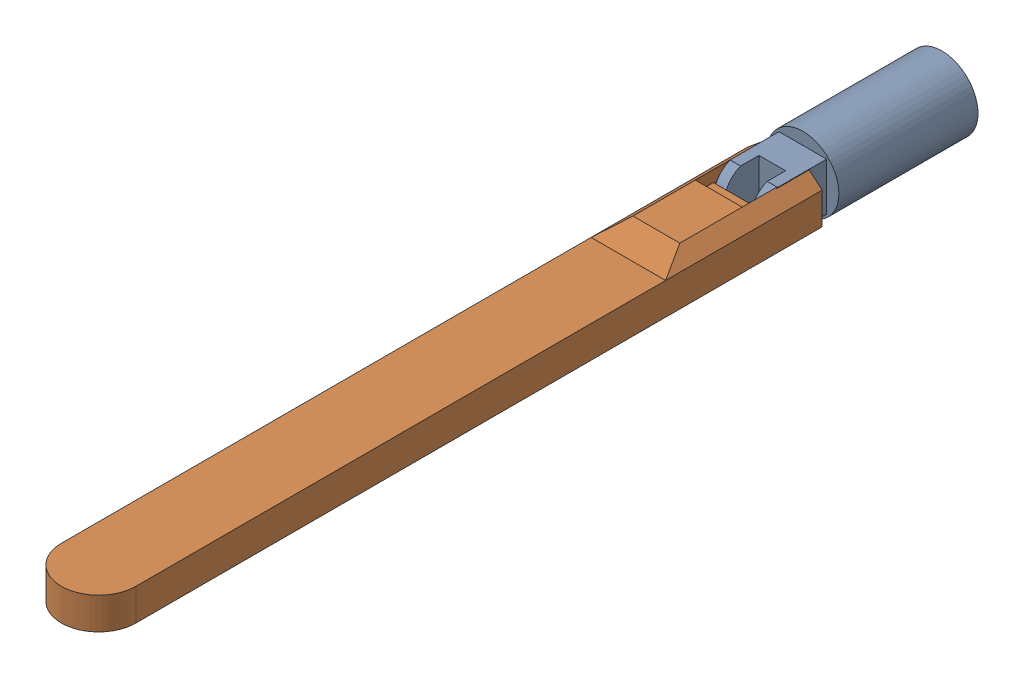
SolidWorks assembly Antannae Assembly, configuration Default. Lengths in mm.
Overall size (13.4 12.95 158.14).
2 component instances, 2 part files, 3 mates.
Components (placement in the parent):
- Antannae for box-1: Antannae for box [Default] at (-76.0672 11.3243 14.0778) size (12.95 12.95 36.74)
- Antannae extender for box-1: Antannae extender for box [Default] at (-76.1605 7.7893 103.8644) x (-1 0 0) z (0 0 -1) size (13.4 9.9 130)
Mates (geometry in assembly coordinates):
- Parallel3: parallel anti-aligned: plane of Antannae for box-1 through (-80.3301 7.0493 47.8778) normal (-1 0 0); plane of Antannae extender for box-1 through (-80.4105 21.1893 50.8144) normal (1 0 0)
- Coincident10: coincident aligned: line of Antannae for box-1 through (-80.3301 15.5993 47.8778) axis (0 0 -1); line of Antannae extender for box-1 through (-80.3301 15.5993 54.1344) axis (0 0 -1)
- Tangent1: tangent anti-aligned: cylinder of Antannae for box-1 through (-78.4501 11.3243 46.2344) axis (-1 0 0) radius 4.58; plane of Antannae extender for box-1 through (-71.9105 21.1893 50.8144) normal (0 0 -1)
